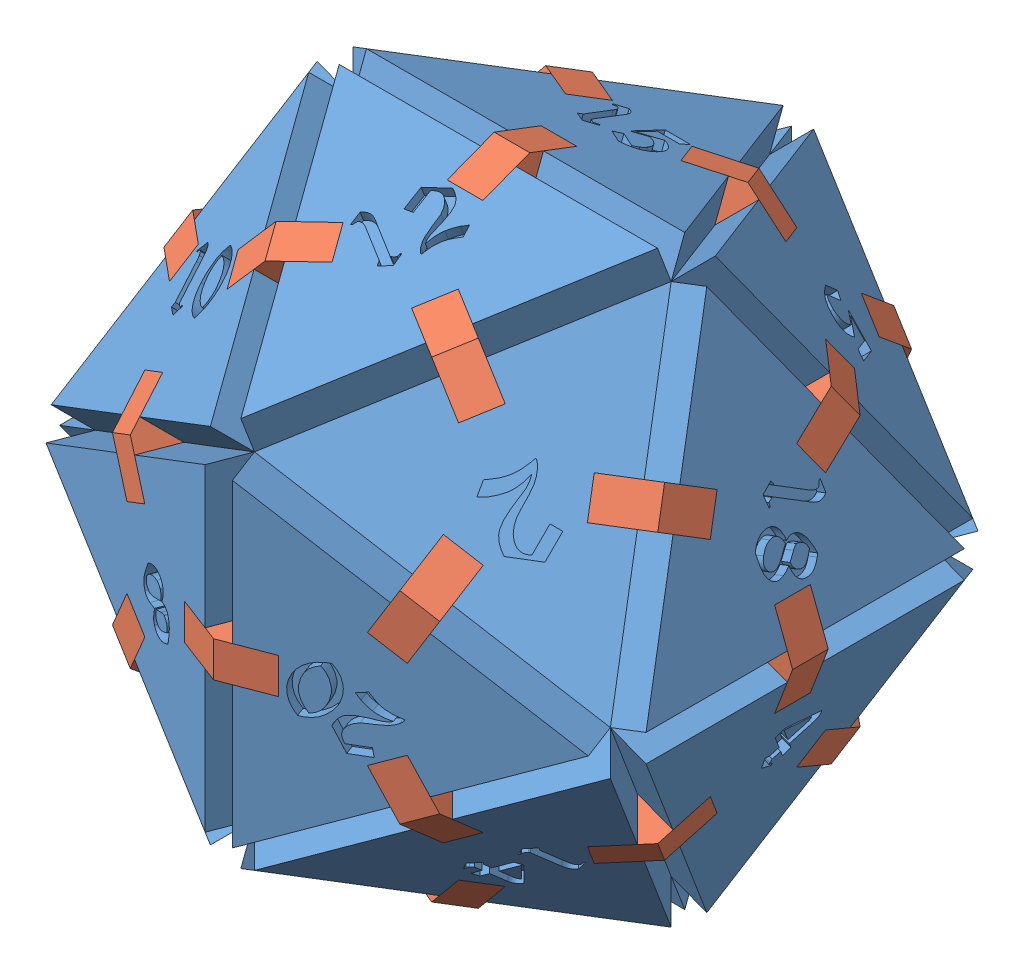
SolidWorks assembly d20, configuration Default. Lengths in mm.
Overall size (55.1 56.41 55.1).
50 component instances, 2 part files, 126 mates.
Components (placement in the parent):
- face-1: face [Default] at (37.1923 82.2358 69.5102) x (1 0 0) z (0 0.356822 0.934172) size (25 3 21.65)
- face-2: face [Default] at (48.1008 75.494 65.3436) x (0.5 0.309017 0.809017) z (-0.645497 0.755761 0.110264) size (25 3 21.65)
- face-3: face [Default] at (37.1923 82.2358 82.9939) x (0.5 0.309017 -0.809017) z (0.866025 -0.178411 0.467086) size (25 3 21.65)
- face-4: face [Default] at (26.2839 75.494 87.1605) x (0.809017 0.5 0.309017) z (0.110264 -0.645497 0.755761) size (25 3 21.65)
- face-5: face [Default] at (48.1008 75.494 87.1605) x (-0.5 -0.309017 0.809017) z (-0.645497 0.755761 -0.110264) size (25 3 21.65)
- face-6: face [Default] at (54.8426 71.3273 76.2521) x (0.309017 -0.809017 0.5) z (-0.178411 0.467086 0.866025) size (25 3 21.65)
- face-7: face [Default] at (30.4505 64.5855 93.9023) x (-0.809017 -0.5 -0.309017) z (-0.467086 0.866025 -0.178411) size (25 3 21.65)
- face-8: face [Default] at (48.1008 53.6771 87.1605) x (-0.809017 -0.5 0.309017) z (-0.110264 0.645497 0.755761) size (25 3 21.65)
- face-9: face [Default] at (54.8426 57.8437 76.2521) x (-0.309017 -0.809017 -0.5) z (-0.178411 -0.467086 0.866025) size (25 3 21.65)
- face-10: face [Default] at (43.9341 64.5855 93.9023) x (-0.809017 0.5 0.309017) z (0.467086 0.866025 -0.178411) size (25 3 21.65)
- face-11: face [Default] at (45.0046 64.5855 55.7993) x (0 -1 0) z (-0.934172 0 -0.356822) size (25 3 21.65)
- face-12: face [Default] at (26.2839 75.494 65.3436) x (0.309017 0.809017 0.5) z (-0.755761 -0.110264 0.645497) size (25 3 21.65)
- face-13: face [Default] at (30.4505 64.5855 58.6018) x (0.809017 0.5 -0.309017) z (-0.467086 0.866025 0.178411) size (25 3 21.65)
- face-14: face [Default] at (48.1008 53.6771 65.3436) x (-0.309017 -0.809017 0.5) z (0.755761 0.110264 0.645497) size (25 3 21.65)
- face-15: face [Default] at (16.7395 72.3978 76.2521) x (0.309017 0.809017 0.5) z (0.178411 0.467086 -0.866025) size (25 3 21.65)
- face-16: face [Default] at (26.2839 53.6771 65.3436) x (0.809017 -0.5 -0.309017) z (0.110264 0.645497 -0.755761) size (25 3 21.65)
- face-17: face [Default] at (37.1923 44.1327 68.4398) x (-0.5 0.309017 -0.809017) z (0.866025 0.178411 -0.467086) size (25 3 21.65)
- face-18: face [Default] at (16.7395 56.7733 76.2521) x (0 0 1) z (-0.356822 0.934172 0) size (25 3 21.65)
- face-19: face [Default] at (24.5518 51.945 88.8926) x (0.809017 -0.5 0.309017) z (0.110264 0.645497 0.755761) size (25 3 21.65)
- face-20: face [Default] at (37.1923 44.1327 84.0643) x (-1 0 0) z (0 -0.356822 -0.934172) size (25 3 21.65)
- connector3-1: connector3 [Default] x (1 0 0) z (0 1 0) size (10.83 9.65 12.81)
- connector3-2: connector3 [Default] at (11.5745 38.8188 -23.9914) x (0.309017 -0.809017 0.5) z (0.809017 0.5 0.309017) size (10.83 9.65 12.81)
- connector3-3: connector3 [Default] at (58.552 41.4505 -25.6178) x (-0.809017 -0.5 0.309017) z (0.5 -0.309017 0.809017) size (10.83 9.65 12.81)
- connector3-4: connector3 [Default] at (76.0112 4.2582 -2.6317) x (-0.809017 0.5 -0.309017) z (-0.5 -0.309017 0.809017) size (10.83 9.65 12.81)
- connector3-5: connector3 [Default] at (39.824 -21.3596 13.201) x (0.309017 0.809017 -0.5) z (-0.809017 0.5 0.309017) size (10.83 9.65 12.81)
- connector3-6: connector3 [Default] at (-63.0511 38.9677 50.4853) x (0.5 0.309017 -0.809017) z (0.309017 0.809017 0.5) size (10.83 9.65 12.81)
- connector3-7: connector3 [Default] at (-64.6775 85.9452 53.117) x (0.309017 -0.809017 -0.5) z (0.809017 0.5 -0.309017) size (10.83 9.65 12.81)
- connector3-8: connector3 [Default] at (-1.6265 124.9129 -2.6317) x (0.809017 -0.5 -0.309017) z (0.5 0.309017 0.809017) size (10.83 9.65 12.81)
- connector3-9: connector3 [Default] at (-41.6914 103.4044 15.9247) x (-0.309017 -0.809017 0.5) z (0.809017 -0.5 -0.309017) size (10.83 9.65 12.81)
- connector3-10: connector3 [Default] at (-27.3932 140.8376 113.4444) x (0 0 -1) z (1 0 0) size (10.83 9.65 12.81)
- connector3-11: connector3 [Default] at (-39.0597 101.7779 140.8376) x (0 -1 0) z (0 0 -1) size (10.83 9.65 12.81)
- connector3-12: connector3 [Default] at (11.4256 164.8289 101.8699) x (-0.809017 -0.5 -0.309017) z (0.5 -0.309017 -0.809017) size (10.83 9.65 12.81)
- connector3-13: connector3 [Default] at (14.0573 166.4554 54.8924) x (-0.5 -0.309017 0.809017) z (-0.309017 -0.809017 -0.5) size (10.83 9.65 12.81)
- connector3-14: connector3 [Default] at (-23.135 143.4693 37.4332) x (0.5 0.309017 0.809017) z (-0.309017 -0.809017 0.5) size (10.83 9.65 12.81)
- connector3-15: connector3 [Default] at (39.824 150.5307 139.3031) x (0.309017 -0.809017 0.5) z (-0.809017 -0.5 -0.309017) size (10.83 9.65 12.81)
- connector3-16: connector3 [Default] at (14.0573 -37.2844 97.6117) x (-0.5 0.309017 -0.809017) z (-0.309017 0.809017 0.5) size (10.83 9.65 12.81)
- connector3-17: connector3 [Default] at (-23.135 -14.2982 115.0709) x (0.5 -0.309017 -0.809017) z (-0.309017 0.809017 -0.5) size (10.83 9.65 12.81)
- connector3-18: connector3 [Default] at (-48.7528 1.5345 78.8838) x (0.809017 -0.5 0.309017) z (0.5 0.309017 -0.809017) size (10.83 9.65 12.81)
- connector3-19: connector3 [Default] at (-1.6265 4.2582 155.1358) x (0.809017 0.5 0.309017) z (0.5 -0.309017 -0.809017) size (10.83 9.65 12.81)
- connector3-20: connector3 [Default] at (62.8102 38.8188 176.4955) x (-0.309017 -0.809017 -0.5) z (-0.809017 0.5 -0.309017) size (10.83 9.65 12.81)
- connector3-21: connector3 [Default] at (62.9591 -35.6579 101.8699) x (0.809017 0.5 -0.309017) z (-0.5 0.309017 -0.809017) size (10.83 9.65 12.81)
- connector3-22: connector3 [Default] at (101.7779 -11.6665 113.4444) x (0 0 -1) z (-1 0 0) size (10.83 9.65 12.81)
- connector3-23: connector3 [Default] at (123.1375 1.5345 73.6204) x (-0.809017 -0.5 -0.309017) z (-0.5 0.309017 0.809017) size (10.83 9.65 12.81)
- connector3-24: connector3 [Default] at (139.0622 43.2259 53.117) x (-0.309017 0.809017 -0.5) z (-0.809017 -0.5 -0.309017) size (10.83 9.65 12.81)
- connector3-25: connector3 [Default] at (15.8327 41.4505 178.1219) x (0.809017 -0.5 -0.309017) z (-0.5 -0.309017 -0.809017) size (10.83 9.65 12.81)
- connector3-26: connector3 [Default] at (100.2434 67.2172 162.1972) x (0.5 0.309017 -0.809017) z (-0.309017 -0.809017 -0.5) size (10.83 9.65 12.81)
- connector3-27: connector3 [Default] at (116.0761 103.4044 136.5794) x (0.309017 -0.809017 -0.5) z (-0.809017 -0.5 0.309017) size (10.83 9.65 12.81)
- connector3-28: connector3 [Default] at (137.4357 90.2034 50.4853) x (-0.5 -0.309017 -0.809017) z (-0.309017 -0.809017 0.5) size (10.83 9.65 12.81)
- connector3-29: connector3 [Default] at (113.4444 101.7779 11.6665) x (0 -1 0) z (0 0 1) size (10.83 9.65 12.81)
- connector3-30: connector3 [Default] at (74.3847 129.1711 0) x (-1 0 0) z (0 -1 0) size (10.83 9.65 12.81)
Mates (geometry in assembly coordinates):
- Coincident86: coincident anti-aligned: line of face-3 through (31.6423 80.5156 87.4974) axis (0.5 -0.309017 0.809017); line of face-4 through (37.1923 77.0855 96.4775) axis (-0.5 0.309017 -0.809017)
- Coincident87: coincident anti-aligned: plane of ? through (19.6923 85.841 78.9488) normal (0 0.934172 -0.356822); plane of face-1 through (37.1923 82.2358 69.5102) normal (0 -0.934172 0.356822)
- Coincident88: coincident anti-aligned: line of face-1 through (38.5923 84.811 76.2521) axis (1 0 0); line of face-3 through (49.6923 84.811 76.2521) axis (-1 0 0)
- Coincident89: coincident anti-aligned: plane of ? through (37.1923 75.0254 50.6332) normal (-0.57735 0.57735 -0.57735); plane of face-12 through (21.9205 72.7973 63.6769) normal (0.57735 -0.57735 0.57735)
- Coincident90: coincident anti-aligned: line of face-1 through (30.2423 81.3809 67.272) axis (-0.5 0.309017 0.809017); line of face-12 through (24.6923 84.811 76.2521) axis (0.5 -0.309017 -0.809017)
- Coincident91: coincident anti-aligned: plane of ? through (65.5079 57.5254 61.4488) normal (0.57735 0.57735 -0.57735); plane of face-2 through (52.4642 72.7973 63.6769) normal (-0.57735 -0.57735 0.57735)
- Coincident92: coincident anti-aligned: line of face-1 through (49.6923 84.811 76.2521) axis (-0.5 -0.309017 -0.809017); line of face-2 through (44.1423 81.3809 67.272) axis (0.5 0.309017 0.809017)
- Coincident93: coincident anti-aligned: plane of ? through (37.1923 75.0254 50.6332) normal (-0.356822 0 -0.934172); plane of face-13 through (27.7538 57.5254 54.2384) normal (0.356822 0 0.934172)
- Coincident94: coincident anti-aligned: line of face-12 through (37.1923 77.0855 56.0266) axis (-0.809017 -0.5 0.309017); line of face-13 through (28.2123 71.5355 59.4567) axis (0.809017 0.5 -0.309017)
- Coincident95: coincident anti-aligned: plane of ? through (65.5079 57.5254 61.4488) normal (0.356822 0 -0.934172); plane of face-11 through (46.6309 57.5254 54.2384) normal (-0.356822 0 0.934172)
- Coincident96: coincident aligned: line of face-11 through (37.1923 77.0855 56.0266) axis (0 -1 0); line of face-13 through (37.1923 77.0855 56.0266) axis (0 -1 0)
- Coincident97: coincident aligned: line of face-2 through (46.1724 71.5355 59.4567) axis (-0.809017 0.5 -0.309017); line of face-11 through (46.1724 71.5355 59.4567) axis (-0.809017 0.5 -0.309017)
- Coincident98: coincident anti-aligned: plane of ? through (54.6923 85.841 78.9488) normal (0.934172 0.356822 0); plane of face-6 through (61.9027 66.964 78.9488) normal (-0.934172 -0.356822 0)
- Coincident99: coincident anti-aligned: line of face-2 through (49.6923 84.811 76.2521) axis (0.309017 -0.809017 -0.5); line of face-6 through (53.1224 75.8309 70.7021) axis (-0.309017 0.809017 0.5)
- Coincident100: coincident anti-aligned: line of face-5 through (53.1224 75.8309 81.8021) axis (-0.309017 0.809017 -0.5); line of face-6 through (49.6923 84.811 76.2521) axis (0.309017 -0.809017 0.5)
- Coincident102: coincident aligned: line of face-12 through (21.2623 75.8309 70.7021) axis (0.309017 0.809017 0.5); line of face-15 through (21.2623 75.8309 70.7021) axis (0.309017 0.809017 0.5)
- Coincident103: coincident aligned: line of face-4 through (24.6923 84.811 76.2521) axis (-0.309017 -0.809017 0.5); line of face-15 through (24.6923 84.811 76.2521) axis (-0.309017 -0.809017 0.5)
- Coincident104: coincident anti-aligned: line of face-3 through (44.1423 81.3809 85.2321) axis (0.5 0.309017 -0.809017); line of face-5 through (49.6923 84.811 76.2521) axis (-0.5 -0.309017 0.809017)
- Coincident105: coincident anti-aligned: line of face-5 through (48.4377 70.1355 92.1821) axis (0.809017 -0.5 -0.309017); line of face-10 through (57.4178 64.5855 88.7521) axis (-0.809017 0.5 0.309017)
- Coincident106: coincident anti-aligned: line of face-7 through (37.1923 65.9855 96.4775) axis (0 1 0); line of face-10 through (37.1923 77.0855 96.4775) axis (0 -1 0)
- Coincident107: coincident anti-aligned: line of face-4 through (28.2123 71.5355 93.0474) axis (0.809017 0.5 0.309017); line of face-7 through (37.1923 77.0855 96.4775) axis (-0.809017 -0.5 -0.309017)
- Coincident108: coincident anti-aligned: line of face-8 through (57.4178 64.5855 88.7521) axis (-0.809017 -0.5 0.309017); line of face-10 through (48.4377 59.0355 92.1821) axis (0.809017 0.5 -0.309017)
- Coincident110: coincident aligned: line of face-7 through (28.2123 57.6355 93.0474) axis (0.809017 -0.5 0.309017); line of face-19 through (28.2123 57.6355 93.0474) axis (0.809017 -0.5 0.309017)
- Coincident111: coincident anti-aligned: line of face-15 through (16.9669 64.5855 88.7521) axis (0 0 -1); line of face-18 through (16.9669 64.5855 77.6521) axis (0 0 1)
- Coincident112: coincident anti-aligned: line of face-18 through (16.9669 64.5855 88.7521) axis (0.309017 -0.809017 -0.5); line of face-19 through (20.397 55.6054 83.2021) axis (-0.309017 0.809017 0.5)
- Coincident113: coincident anti-aligned: line of face-19 through (30.2423 47.7902 85.2321) axis (-0.5 -0.309017 -0.809017); line of face-20 through (24.6923 44.3601 76.2521) axis (0.5 0.309017 0.809017)
- Coincident114: coincident aligned: line of face-8 through (44.1423 47.7902 85.2321) axis (0.5 -0.309017 -0.809017); line of face-20 through (44.1423 47.7902 85.2321) axis (0.5 -0.309017 -0.809017)
- Coincident115: coincident anti-aligned: line of face-8 through (49.6923 44.3601 76.2521) axis (0.309017 0.809017 0.5); line of face-9 through (53.1224 53.3402 81.8021) axis (-0.309017 -0.809017 -0.5)
- Coincident118: coincident anti-aligned: line of face-6 through (57.4178 64.5855 74.8521) axis (0 0 -1); line of face-9 through (57.4178 64.5855 63.7521) axis (0 0 1)
- Coincident119: coincident aligned: line of face-16 through (24.6923 44.3601 76.2521) axis (-0.309017 0.809017 -0.5); line of face-18 through (24.6923 44.3601 76.2521) axis (-0.309017 0.809017 -0.5)
- Coincident120: coincident anti-aligned: line of face-17 through (24.6923 44.3601 76.2521) axis (1 0 0); line of face-20 through (35.7923 44.3601 76.2521) axis (-1 0 0)
- Coincident121: coincident aligned: line of face-16 through (30.2423 47.7902 67.272) axis (-0.5 -0.309017 0.809017); line of face-17 through (30.2423 47.7902 67.272) axis (-0.5 -0.309017 0.809017)
- Coincident122: coincident aligned: line of face-14 through (49.6923 44.3601 76.2521) axis (-0.5 0.309017 -0.809017); line of face-17 through (49.6923 44.3601 76.2521) axis (-0.5 0.309017 -0.809017)
- Coincident123: coincident anti-aligned: line of face-9 through (49.6923 44.3601 76.2521) axis (0.309017 0.809017 -0.5); line of face-14 through (53.1224 53.3402 70.7021) axis (-0.309017 -0.809017 0.5)
- InPlace1: in place: plane of ? through (0 0 0) normal (0 1 0); moOrthogonalPlaneRef_w of ? through (0 0 0) normal (0 0 1); plane of ? through (0 0 0) normal (-1 0 0); unknown of connector3-1
- Coincident124: coincident aligned: plane of connector3-1; plane of assembly
- Coincident125: coincident aligned: plane of connector3-1 through (0 0 0) normal (0 0 -1); moOrthogonalPlaneRef_w of assembly
- Coincident126: coincident anti-aligned: plane of connector3-1 through (0 0 0) normal (1 0 0); moOrthogonalPlaneRef_w of assembly
- Width1: width aligned: plane of connector3-2 through (-6.0095 49.6863 -17.2749) normal (0.809017 -0.5 -0.309017); plane of connector3-2 through (-8.2747 51.0863 -16.4096) normal (-0.809017 0.5 0.309017); plane of face-10 through (46.1721 71.5355 93.0465) normal (0.809017 -0.5 -0.309017); plane of face-10 through (48.4373 70.1355 92.1812) normal (-0.809017 0.5 0.309017)
- Coincident127: coincident aligned: plane of face-5 through (49.8329 77.2261 88.8926) normal (0.57735 0.57735 0.57735); plane of connector3-2 through (50.1697 71.8676 93.9142) normal (0.57735 0.57735 0.57735)
- Coincident128: coincident aligned: plane of face-10 through (45.0046 64.5855 96.7049) normal (0.356822 0 0.934172); plane of connector3-2 through (48.2003 67.7107 95.4842) normal (0.356822 0 0.934172)
- Width2: width aligned: plane of face-7 through (37.1927 63.1855 96.4765) normal (0 1 0); plane of face-7 through (37.1927 65.9855 96.4765) normal (0 -1 0); plane of connector3-3 through (58.552 65.9855 -25.6178) normal (0 1 0); plane of connector3-3 through (58.552 63.1855 -25.6178) normal (0 -1 0)
- Coincident129: coincident aligned: plane of face-7 through (29.3801 64.5855 96.7049) normal (-0.356822 0 0.934172); plane of connector3-3 through (33.5062 63.1855 98.2809) normal (-0.356822 0 0.934172)
- Coincident130: coincident aligned: plane of face-10 through (45.0046 64.5855 96.7049) normal (0.356822 0 0.934172); plane of connector3-3 through (38.2628 63.1855 99.28) normal (0.356822 0 0.934172)
- Width3: width aligned: plane of face-4 through (28.2128 71.535 93.0468) normal (-0.809017 -0.5 -0.309017); plane of face-4 through (25.9476 70.135 92.1816) normal (0.809017 0.5 0.309017); plane of connector3-4 through (93.5952 15.1257 4.0848) normal (-0.809017 -0.5 -0.309017); plane of connector3-4 through (95.8604 16.5257 4.95) normal (0.809017 0.5 0.309017)
- Coincident131: coincident aligned: plane of face-7 through (29.3801 64.5855 96.7049) normal (-0.356822 0 0.934172); plane of connector3-4 through (24.8765 70.1355 94.9847) normal (-0.356822 0 0.934172)
- Coincident132: coincident aligned: plane of face-4 through (24.5518 77.2261 88.8926) normal (-0.57735 0.57735 0.57735); plane of connector3-4 through (23.9062 73.675 91.7981) normal (-0.57735 0.57735 0.57735)
- Width4: width aligned: plane of connector3-5 through (50.6915 -28.0761 30.785) normal (-0.5 0.309017 -0.809017); plane of connector3-5 through (52.0915 -28.9414 33.0502) normal (0.5 -0.309017 0.809017); plane of face-3 through (31.6423 80.5147 87.497) normal (-0.5 0.309017 -0.809017); plane of face-3 through (30.2423 81.3799 85.2318) normal (0.5 -0.309017 0.809017)
- Coincident133: coincident aligned: plane of face-4 through (24.5518 77.2261 88.8926) normal (-0.57735 0.57735 0.57735); plane of connector3-5 through (28.5103 83.1129 86.9642) normal (-0.57735 0.57735 0.57735)
- Coincident134: coincident aligned: plane of face-3 through (37.1923 85.0383 84.0643) normal (0 0.934172 0.356822); plane of connector3-5 through (32.6672 84.6829 84.9948) normal (0 0.934172 0.356822)
- Coincident136: coincident anti-aligned: line of face-13 through (37.1923 52.0855 56.0266) axis (-0.809017 0.5 0.309017); line of face-16 through (28.2123 57.6355 59.4567) axis (0.809017 -0.5 -0.309017)
- Width5: width aligned: plane of face-5 through (53.9871 73.565 83.2015) normal (-0.309017 0.809017 -0.5); plane of face-5 through (53.1218 75.8303 81.8015) normal (0.309017 -0.809017 0.5); plane of connector3-6 through (-56.3346 21.3837 61.3528) normal (-0.309017 0.809017 -0.5); plane of connector3-6 through (-55.4693 19.1185 62.7528) normal (0.309017 -0.809017 0.5)
- Coincident137: coincident aligned: plane of face-6 through (57.6451 72.3978 76.2521) normal (0.934172 0.356822 0); plane of connector3-6 through (56.4245 75.5935 79.3772) normal (0.934172 0.356822 0)
- Coincident138: coincident aligned: plane of face-5 through (49.8329 77.2261 88.8926) normal (0.57735 0.57735 0.57735); plane of connector3-6 through (54.8545 77.5629 83.5341) normal (0.57735 0.57735 0.57735)
- Width6: width anti-aligned: plane of face-9 through (57.4168 64.5859 74.8521) normal (0 0 1); plane of face-9 through (57.4168 64.5859 77.6521) normal (0 0 -1); plane of connector3-7 through (-64.6775 85.9452 74.8521) normal (0 0 -1); plane of connector3-7 through (-64.6775 85.9452 77.6521) normal (0 0 1)
- Coincident139: coincident aligned: plane of face-9 through (57.6451 56.7733 76.2521) normal (0.934172 -0.356822 0); plane of connector3-7 through (59.2212 60.8994 74.8521) normal (0.934172 -0.356822 0)
- Coincident140: coincident aligned: plane of face-6 through (57.6451 72.3978 76.2521) normal (0.934172 0.356822 0); plane of connector3-7 through (60.2203 65.656 74.8521) normal (0.934172 0.356822 0)
- Width7: width aligned: plane of face-10 through (46.1721 57.6355 93.0465) normal (0.809017 0.5 -0.309017); plane of face-10 through (48.4373 59.0355 92.1812) normal (-0.809017 -0.5 0.309017); plane of connector3-8 through (-19.2105 114.0454 4.0848) normal (0.809017 0.5 -0.309017); plane of connector3-8 through (-21.4757 112.6454 4.95) normal (-0.809017 -0.5 0.309017)
- Coincident141: coincident aligned: plane of face-8 through (49.8329 51.945 88.8926) normal (0.57735 -0.57735 0.57735); plane of connector3-8 through (50.4785 55.4961 91.7981) normal (0.57735 -0.57735 0.57735)
- Coincident142: coincident aligned: plane of face-10 through (45.0046 64.5855 96.7049) normal (0.356822 0 0.934172); plane of connector3-8 through (49.5081 59.0355 94.9847) normal (0.356822 0 0.934172)
- Width8: width anti-aligned: plane of connector3-9 through (-34.1097 123.2536 28.1922) normal (0.309017 0.809017 0.5); plane of connector3-9 through (-34.9749 120.9883 26.7922) normal (-0.309017 -0.809017 -0.5); plane of face-8 through (53.9871 55.606 83.2015) normal (-0.309017 -0.809017 -0.5); plane of face-8 through (53.1218 53.3408 81.8015) normal (0.309017 0.809017 0.5)
- Coincident146: coincident aligned: plane of face-8 through (49.8329 51.945 88.8926) normal (0.57735 -0.57735 0.57735); plane of connector3-9 through (52.7383 51.2994 85.3415) normal (0.57735 -0.57735 0.57735)
- Coincident147: coincident aligned: plane of face-9 through (57.6451 56.7733 76.2521) normal (0.934172 -0.356822 0); plane of connector3-9 through (55.9249 52.2697 81.8021) normal (0.934172 -0.356822 0)
- Width9: width aligned: plane of connector3-10 through (-34.1097 123.2536 124.3119) normal (0.309017 0.809017 -0.5); plane of connector3-10 through (-34.9749 120.9883 125.7119) normal (-0.309017 -0.809017 0.5); plane of face-9 through (53.1215 53.3406 70.7021) normal (0.309017 0.809017 -0.5); plane of face-9 through (53.9867 55.6058 69.3021) normal (-0.309017 -0.809017 0.5)
- Coincident148: coincident aligned: plane of face-14 through (49.8329 51.945 63.6115) normal (0.57735 -0.57735 -0.57735); plane of connector3-10 through (53.6036 53.5647 65.7626) normal (0.57735 -0.57735 -0.57735)
- Coincident149: coincident aligned: plane of face-9 through (57.6451 56.7733 76.2521) normal (0.934172 -0.356822 0); plane of connector3-10 through (56.7902 54.535 69.3021) normal (0.934172 -0.356822 0)
- Coincident150: coincident aligned: plane of face-14 through (49.8329 51.945 63.6115) normal (0.57735 -0.57735 -0.57735); plane of connector3-11 through (48.2132 54.0961 59.8408) normal (0.57735 -0.57735 -0.57735)
- Coincident151: coincident aligned: plane of face-11 through (45.0046 64.5855 55.7993) normal (0.356822 0 -0.934172); plane of connector3-11 through (47.2429 57.6355 56.6542) normal (0.356822 0 -0.934172)
- Width10: width aligned: plane of connector3-11 through (-19.2105 114.0454 148.4193) normal (0.809017 0.5 0.309017); plane of connector3-11 through (-21.4757 112.6454 147.5541) normal (-0.809017 -0.5 -0.309017); plane of face-11 through (47.2433 57.6355 56.6533) normal (0.809017 0.5 0.309017); plane of face-11 through (49.5085 59.0355 57.5185) normal (-0.809017 -0.5 -0.309017)
- Coincident152: coincident aligned: plane of face-14 through (49.8329 51.945 63.6115) normal (0.57735 -0.57735 -0.57735); plane of connector3-12 through (44.4744 46.9234 63.2747) normal (0.57735 -0.57735 -0.57735)
- Coincident153: coincident aligned: plane of face-17 through (37.1923 44.1327 68.4398) normal (0 -0.934172 -0.356822); plane of connector3-12 through (40.3175 45.3534 65.2441) normal (0 -0.934172 -0.356822)
- Width11: width aligned: plane of connector3-12 through (22.2931 158.1125 119.4539) normal (-0.5 0.309017 -0.809017); plane of connector3-12 through (23.6931 157.2472 121.7191) normal (0.5 -0.309017 0.809017); plane of face-14 through (44.1418 47.7908 67.2725) normal (-0.5 0.309017 -0.809017); plane of face-14 through (42.7418 48.656 65.0073) normal (0.5 -0.309017 0.809017)
- Width12: width aligned: plane of connector3-13 through (38.5923 166.4554 54.8924) normal (1 0 0); plane of connector3-13 through (35.7923 166.4554 54.8924) normal (-1 0 0); plane of face-20 through (35.7923 41.5567 77.3229) normal (1 0 0); plane of face-20 through (38.5923 41.5567 77.3229) normal (-1 0 0)
- Coincident154: coincident aligned: plane of face-17 through (37.1923 44.1327 68.4398) normal (0 -0.934172 -0.356822); plane of connector3-13 through (35.7923 41.5576 75.1816) normal (0 -0.934172 -0.356822)
- Coincident155: coincident aligned: plane of face-20 through (37.1923 44.1327 84.0643) normal (0 -0.934172 0.356822); plane of connector3-13 through (35.7923 42.5567 79.9382) normal (0 -0.934172 0.356822)
- Width13: width anti-aligned: plane of face-20 through (42.7423 45.852 88.5682) normal (0.5 -0.309017 -0.809017); plane of face-20 through (44.1423 44.9867 86.303) normal (-0.5 0.309017 0.809017); plane of connector3-14 through (-12.2675 136.7528 19.8492) normal (-0.5 0.309017 0.809017); plane of connector3-14 through (-10.8675 135.8876 17.584) normal (0.5 -0.309017 -0.809017)
- Coincident156: coincident aligned: plane of face-8 through (49.8329 51.945 88.8926) normal (0.57735 -0.57735 0.57735); plane of connector3-14 through (46.2818 49.0395 89.5382) normal (0.57735 -0.57735 0.57735)
- Coincident157: coincident aligned: plane of face-20 through (37.1923 44.1327 84.0643) normal (0 -0.934172 0.356822); plane of connector3-14 through (42.7423 45.8529 88.5679) normal (0 -0.934172 0.356822)
- Width14: width aligned: plane of face-17 through (31.6423 45.852 63.9359) normal (-0.5 -0.309017 0.809017); plane of face-17 through (30.2423 44.9867 66.2011) normal (0.5 0.309017 -0.809017); plane of connector3-15 through (50.6915 157.2472 121.7191) normal (-0.5 -0.309017 0.809017); plane of connector3-15 through (52.0915 158.1125 119.4539) normal (0.5 0.309017 -0.809017)
- Coincident158: coincident aligned: plane of face-17 through (37.1923 44.1327 68.4398) normal (0 -0.934172 -0.356822); plane of connector3-15 through (32.6672 44.4881 67.5093) normal (0 -0.934172 -0.356822)
- Coincident159: coincident aligned: plane of face-16 through (24.5518 51.945 63.6115) normal (-0.57735 -0.57735 -0.57735); plane of connector3-15 through (28.5103 46.0581 65.5399) normal (-0.57735 -0.57735 -0.57735)
- Width15: width anti-aligned: plane of face-1 through (35.7923 84.81 76.2524) normal (1 0 0); plane of face-1 through (38.5923 84.81 76.2524) normal (-1 0 0); plane of connector3-16 through (35.7923 -37.2844 97.6117) normal (-1 0 0); plane of connector3-16 through (38.5923 -37.2844 97.6117) normal (1 0 0)
- Coincident160: coincident aligned: plane of face-3 through (37.1923 85.0383 84.0643) normal (0 0.934172 0.356822); plane of connector3-16 through (35.7923 87.6135 77.3225) normal (0 0.934172 0.356822)
- Coincident161: coincident aligned: plane of face-1 through (37.1923 85.0383 68.4398) normal (0 0.934172 -0.356822); plane of connector3-16 through (35.7923 86.6144 72.5659) normal (0 0.934172 -0.356822)
- Coincident162: coincident aligned: plane of face-1 through (37.1923 85.0383 68.4398) normal (0 0.934172 -0.356822); plane of connector3-17 through (42.7423 83.3181 63.9363) normal (0 0.934172 -0.356822)
- Coincident163: coincident aligned: plane of face-2 through (49.8329 77.2261 63.6115) normal (0.57735 0.57735 -0.57735); plane of connector3-17 through (46.2818 80.1315 62.9659) normal (0.57735 0.57735 -0.57735)
- Width16: width aligned: plane of connector3-17 through (-10.8675 -6.7165 134.9201) normal (0.5 0.309017 0.809017); plane of connector3-17 through (-12.2675 -7.5817 132.6549) normal (-0.5 -0.309017 -0.809017); plane of face-1 through (42.7423 80.5147 65.0071) normal (0.5 0.309017 0.809017); plane of face-1 through (44.1423 81.3799 67.2723) normal (-0.5 -0.309017 -0.809017)
- Coincident164: coincident aligned: plane of face-6 through (57.6451 72.3978 76.2521) normal (0.934172 0.356822 0); plane of connector3-18 through (57.2897 73.3282 71.7269) normal (0.934172 0.356822 0)
- Coincident165: coincident aligned: plane of face-2 through (49.8329 77.2261 63.6115) normal (0.57735 0.57735 -0.57735); plane of connector3-18 through (55.7197 75.2977 67.57) normal (0.57735 0.57735 -0.57735)
- Width17: width anti-aligned: plane of face-2 through (53.9871 73.565 69.3026) normal (-0.309017 0.809017 0.5); plane of face-2 through (53.1218 75.8303 70.7026) normal (0.309017 -0.809017 -0.5); plane of connector3-18 through (-55.4693 19.1185 89.7513) normal (0.309017 -0.809017 -0.5); plane of connector3-18 through (-56.3346 21.3837 91.1513) normal (-0.309017 0.809017 0.5)
- Coincident166: coincident aligned: plane of face-2 through (49.8329 77.2261 63.6115) normal (0.57735 0.57735 -0.57735); plane of connector3-19 through (50.4785 73.675 60.706) normal (0.57735 0.57735 -0.57735)
- Coincident167: coincident aligned: plane of face-11 through (45.0046 64.5855 55.7993) normal (0.356822 0 -0.934172); plane of connector3-19 through (49.5081 70.1355 57.5194) normal (0.356822 0 -0.934172)
- Width18: width anti-aligned: plane of face-11 through (47.2433 71.5355 56.6533) normal (0.809017 -0.5 0.309017); plane of face-11 through (49.5085 70.1355 57.5185) normal (-0.809017 0.5 -0.309017); plane of connector3-19 through (-21.4757 16.5257 147.5541) normal (-0.809017 0.5 -0.309017); plane of connector3-19 through (-19.2105 15.1257 148.4193) normal (0.809017 -0.5 0.309017)
- Coincident168: coincident aligned: plane of face-12 through (24.5518 77.2261 63.6115) normal (-0.57735 0.57735 -0.57735); plane of connector3-20 through (24.215 71.8676 58.5899) normal (-0.57735 0.57735 -0.57735)
- Coincident169: coincident aligned: plane of face-13 through (29.3801 64.5855 55.7993) normal (-0.356822 0 -0.934172); plane of connector3-20 through (26.1844 67.7107 57.0199) normal (-0.356822 0 -0.934172)
- Width19: width anti-aligned: plane of face-12 through (25.9476 70.135 60.3225) normal (0.809017 0.5 -0.309017); plane of face-12 through (28.2128 71.535 59.4573) normal (-0.809017 -0.5 0.309017); plane of connector3-20 through (80.3942 49.6863 169.779) normal (-0.809017 -0.5 0.309017); plane of connector3-20 through (82.6594 51.0863 168.9137) normal (0.809017 0.5 -0.309017)
- Width20: width aligned: plane of connector3-21 through (52.0915 -28.9414 119.4539) normal (0.5 -0.309017 -0.809017); plane of connector3-21 through (50.6915 -28.0761 121.7191) normal (-0.5 0.309017 0.809017); plane of face-1 through (30.2423 81.3799 67.2723) normal (0.5 -0.309017 -0.809017); plane of face-1 through (31.6423 80.5147 65.0071) normal (-0.5 0.309017 0.809017)
- Coincident170: coincident aligned: plane of face-1 through (37.1923 85.0383 68.4398) normal (0 0.934172 -0.356822); plane of connector3-21 through (34.0672 83.8177 65.2441) normal (0 0.934172 -0.356822)
- Coincident171: coincident aligned: plane of face-12 through (24.5518 77.2261 63.6115) normal (-0.57735 0.57735 -0.57735); plane of connector3-21 through (29.9103 82.2477 63.2747) normal (-0.57735 0.57735 -0.57735)
- Coincident172: coincident aligned: plane of face-12 through (24.5518 77.2261 63.6115) normal (-0.57735 0.57735 -0.57735); plane of connector3-22 through (20.7811 75.6064 65.7626) normal (-0.57735 0.57735 -0.57735)
- Coincident173: coincident aligned: plane of face-15 through (16.7395 72.3978 76.2521) normal (-0.934172 0.356822 0); plane of connector3-22 through (17.5945 74.6361 69.3021) normal (-0.934172 0.356822 0)
- Width21: width anti-aligned: plane of connector3-22 through (109.3596 8.1827 125.7119) normal (0.309017 0.809017 0.5); plane of connector3-22 through (108.4944 5.9175 124.3119) normal (-0.309017 -0.809017 -0.5); plane of face-15 through (18.4588 76.9017 70.7021) normal (-0.309017 -0.809017 -0.5); plane of face-15 through (17.5936 74.6364 69.3021) normal (0.309017 0.809017 0.5)
- Coincident174: coincident aligned: plane of face-4 through (24.5518 77.2261 88.8926) normal (-0.57735 0.57735 0.57735); plane of connector3-23 through (18.665 75.2977 84.9341) normal (-0.57735 0.57735 0.57735)
- Coincident175: coincident aligned: plane of face-15 through (16.7395 72.3978 76.2521) normal (-0.934172 0.356822 0); plane of connector3-23 through (17.0949 73.3282 80.7772) normal (-0.934172 0.356822 0)
- Width22: width anti-aligned: plane of connector3-23 through (129.854 19.1185 62.7528) normal (-0.309017 -0.809017 0.5); plane of connector3-23 through (130.7193 21.3837 61.3528) normal (0.309017 0.809017 -0.5); plane of face-4 through (20.3976 73.565 83.2015) normal (0.309017 0.809017 -0.5); plane of face-4 through (21.2628 75.8303 81.8015) normal (-0.309017 -0.809017 0.5)
- Coincident176: coincident aligned: plane of face-15 through (16.7395 72.3978 76.2521) normal (-0.934172 0.356822 0); plane of connector3-24 through (15.1635 68.2717 74.8521) normal (-0.934172 0.356822 0)
- Coincident177: coincident aligned: plane of face-18 through (16.7395 56.7733 76.2521) normal (-0.934172 -0.356822 0); plane of connector3-24 through (14.1644 63.5151 74.8521) normal (-0.934172 -0.356822 0)
- Width23: width anti-aligned: plane of connector3-24 through (139.0622 43.2259 77.6521) normal (0 0 1); plane of connector3-24 through (139.0622 43.2259 74.8521) normal (0 0 -1); plane of face-18 through (14.1635 63.5147 77.6521) normal (0 0 -1); plane of face-18 through (14.1635 63.5147 74.8521) normal (0 0 1)
- Coincident178: coincident aligned: plane of face-13 through (29.3801 64.5855 55.7993) normal (-0.356822 0 -0.934172); plane of connector3-25 through (36.1219 63.1855 53.2241) normal (-0.356822 0 -0.934172)
- Coincident179: coincident aligned: plane of face-11 through (45.0046 64.5855 55.7993) normal (0.356822 0 -0.934172); plane of connector3-25 through (40.8785 63.1855 54.2232) normal (0.356822 0 -0.934172)
- Width24: width anti-aligned: plane of face-13 through (37.1927 65.9855 56.0276) normal (0 -1 0); plane of face-13 through (37.1927 63.1855 56.0276) normal (0 1 0); plane of connector3-25 through (15.8327 65.9855 178.1219) normal (0 1 0); plane of connector3-25 through (15.8327 63.1855 178.1219) normal (0 -1 0)
- Coincident180: coincident aligned: plane of face-13 through (29.3801 64.5855 55.7993) normal (-0.356822 0 -0.934172); plane of connector3-26 through (28.4496 60.0604 56.1547) normal (-0.356822 0 -0.934172)
- Coincident181: coincident aligned: plane of face-16 through (24.5518 51.945 63.6115) normal (-0.57735 -0.57735 -0.57735); plane of connector3-26 through (26.4802 55.9035 57.7247) normal (-0.57735 -0.57735 -0.57735)
- Width25: width anti-aligned: plane of face-13 through (25.9474 59.0355 60.3229) normal (0.809017 -0.5 -0.309017); plane of face-13 through (28.2126 57.6355 59.4577) normal (-0.809017 0.5 0.309017); plane of connector3-26 through (80.3942 79.4847 169.779) normal (-0.809017 0.5 0.309017); plane of connector3-26 through (82.6594 78.0847 168.9137) normal (0.809017 -0.5 -0.309017)
- Coincident182: coincident aligned: plane of face-18 through (16.7395 56.7733 76.2521) normal (-0.934172 -0.356822 0); plane of connector3-27 through (18.4597 52.2697 70.7021) normal (-0.934172 -0.356822 0)
- Coincident183: coincident aligned: plane of face-16 through (24.5518 51.945 63.6115) normal (-0.57735 -0.57735 -0.57735); plane of connector3-27 through (21.6463 51.2994 67.1626) normal (-0.57735 -0.57735 -0.57735)
- Width26: width anti-aligned: plane of connector3-27 through (108.4944 123.2536 124.3119) normal (-0.309017 0.809017 -0.5); plane of connector3-27 through (109.3596 120.9883 125.7119) normal (0.309017 -0.809017 0.5); plane of face-16 through (20.3976 55.606 69.3026) normal (0.309017 -0.809017 0.5); plane of face-16 through (21.2628 53.3408 70.7026) normal (-0.309017 0.809017 -0.5)
- Coincident184: coincident aligned: plane of face-18 through (16.7395 56.7733 76.2521) normal (-0.934172 -0.356822 0); plane of connector3-28 through (17.9602 53.5776 79.3772) normal (-0.934172 -0.356822 0)
- Coincident185: coincident aligned: plane of face-19 through (24.5518 51.945 88.8926) normal (-0.57735 -0.57735 0.57735); plane of connector3-28 through (19.5302 51.6081 83.5341) normal (-0.57735 -0.57735 0.57735)
- Width27: width anti-aligned: plane of face-18 through (17.5936 54.5346 83.2021) normal (0.309017 -0.809017 -0.5); plane of face-18 through (18.4588 52.2694 81.8021) normal (-0.309017 0.809017 0.5); plane of connector3-28 through (129.854 110.0526 62.7528) normal (-0.309017 0.809017 0.5); plane of connector3-28 through (130.7193 107.7874 61.3528) normal (0.309017 -0.809017 -0.5)
- Coincident186: coincident aligned: plane of face-7 through (29.3801 64.5855 96.7049) normal (-0.356822 0 0.934172); plane of connector3-29 through (27.1418 57.6355 95.8499) normal (-0.356822 0 0.934172)
- Coincident187: coincident aligned: plane of face-19 through (24.5518 51.945 88.8926) normal (-0.57735 -0.57735 0.57735); plane of connector3-29 through (26.1715 54.0961 92.6633) normal (-0.57735 -0.57735 0.57735)
- Width28: width anti-aligned: plane of connector3-29 through (93.5952 114.0454 4.0848) normal (-0.809017 0.5 -0.309017); plane of connector3-29 through (95.8604 112.6454 4.95) normal (0.809017 -0.5 0.309017); plane of face-7 through (25.9474 59.0355 92.1812) normal (0.809017 -0.5 0.309017); plane of face-7 through (28.2126 57.6355 93.0465) normal (-0.809017 0.5 -0.309017)
- Coincident188: coincident aligned: plane of face-19 through (24.5518 51.945 88.8926) normal (-0.57735 -0.57735 0.57735); plane of connector3-30 through (26.7029 48.1743 87.2729) normal (-0.57735 -0.57735 0.57735)
- Coincident189: coincident aligned: plane of face-20 through (37.1923 44.1327 84.0643) normal (0 -0.934172 0.356822); plane of connector3-30 through (30.2423 44.9877 86.3026) normal (0 -0.934172 0.356822)
- Width29: width anti-aligned: plane of face-19 through (29.9097 46.9228 89.23) normal (-0.5 -0.309017 -0.809017); plane of face-19 through (28.5097 46.0576 86.9648) normal (0.5 0.309017 0.809017); plane of connector3-30 through (86.6522 136.7528 19.8492) normal (0.5 0.309017 0.809017); plane of connector3-30 through (85.2522 135.8876 17.584) normal (-0.5 -0.309017 -0.809017)
